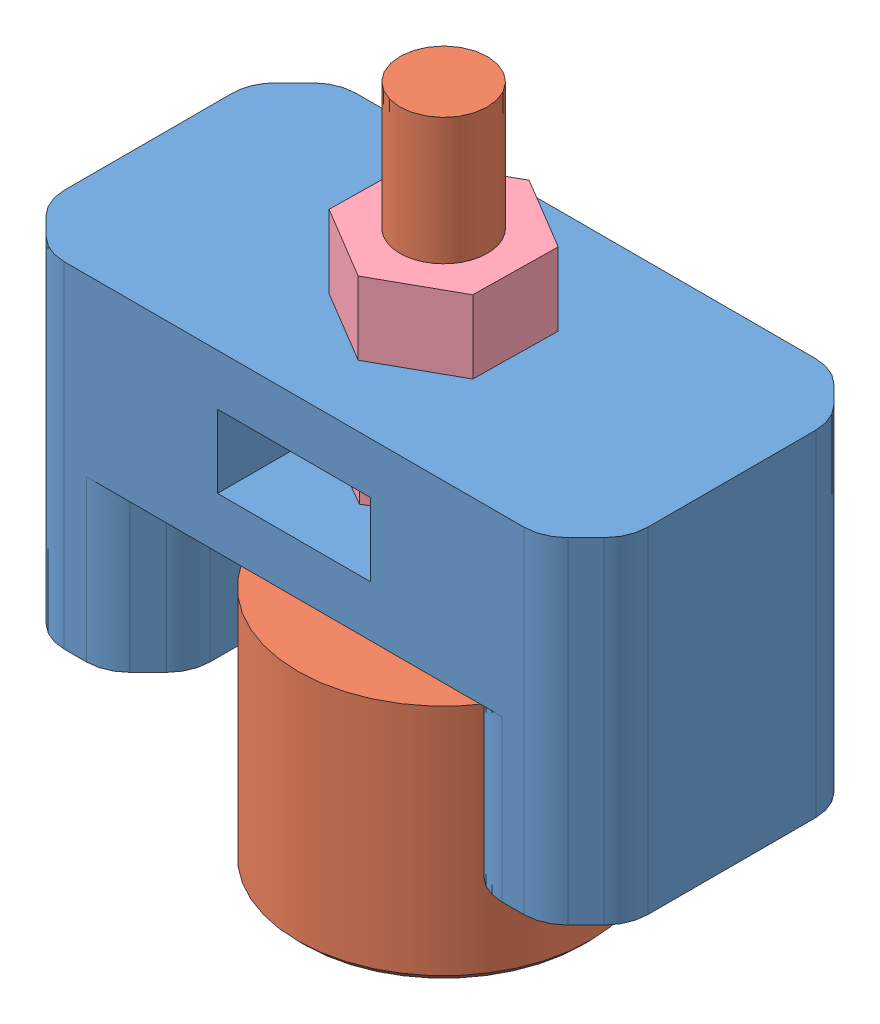
SolidWorks assembly Assemblage Roue Porteuse V2, configuration Défaut. Lengths in mm.
Overall size (40 48.37 24.74).
7 component instances, 5 part files, 13 mates.
Components (placement in the parent):
- Support Bille porteuse V3-1: Support Bille porteuse V3 [Défaut] at (-2.1983 -9.4956 40) size (40 23 20)
- Bille porteuse ALWAYE D12_7-1: Bille porteuse ALWAYE D12_7 [Défaut] at (-1.9483 -8.8075 40) x (-0.275852 0 0.9612) z (-0.9612 0 -0.275852) size (20 46.5 20)
- Bille D12-1: Bille D12 [Défaut] at (-1.9483 -15.1809 40) x (-0.936061 0 0.351838) z (-0.351838 0 -0.936061) size (12 12 12)
- Ecrou M6-3: Ecrou M6 [Défaut] at (-1.9483 13.5044 40) x (0.999888 0 0.014972) z (-0.014972 0 0.999888) size (10 5 11.55)
- Ecrou M6-4: Ecrou M6 [Défaut] at (-1.9483 5.0044 40) size (10 5 11.55)
- Insert_M3x8x5-1: Insert_M3x8x5 [Défaut] at (-17.1983 -9.4956 40) size (4 8 4)
- Insert_M3x8x5-2: Insert_M3x8x5 [Défaut] at (12.8017 -9.4956 40) size (4 8 4)
Mates (geometry in assembly coordinates):
- Coaxiale6: concentric: cylinder of Bille porteuse ALWAYE D12_7-1 through (-1.9483 -18.8075 40) axis (0 1 0) radius 6.75; sphere of Bille D12-1
- Tangent5: tangent: circle of Bille porteuse ALWAYE D12_7-1; sphere of Bille D12-1
- Verrouiller1: lock: unknown of Bille porteuse ALWAYE D12_7-1; unknown of Bille D12-1
- Coïncidente5: coincident anti-aligned: plane of Support Bille porteuse V2-1 through (3.0517 10.0044 30) normal (-1 0 0); plane of Ecrou M6-4 through (3.0517 10.0044 37.1132) normal (1 0 0)
- Coaxiale7: concentric aligned: cylinder of Bille porteuse ALWAYE D12_7-1 through (-1.9483 27.1925 40) axis (0 -1 0) radius 3; cylinder of Ecrou M6-4 through (-1.9483 10.0044 40) axis (0 -1 0) radius 3
- Coïncidente6: coincident anti-aligned: plane of Support Bille porteuse V2-1 through (-2.1983 5.0044 40) normal (0 1 0); plane of Ecrou M6-4 through (-1.9483 5.0044 40) normal (0 -1 0)
- Coaxiale8: concentric aligned: cylinder of Bille porteuse ALWAYE D12_7-1 through (-1.9483 27.1925 40) axis (0 -1 0) radius 3; cylinder of Ecrou M6-3 through (-1.9483 18.5044 40) axis (0 -1 0) radius 3
- Coïncidente7: coincident anti-aligned: plane of Support Bille porteuse V2-1 through (-2.1983 13.5044 40) normal (0 1 0); plane of Ecrou M6-3 through (-1.9483 13.5044 40) normal (0 -1 0)
- Coïncidente8: coincident: point of Support Bille porteuse V2-1; unknown of Ecrou M6-4
- Coaxiale9: concentric: cylinder of Support Bille porteuse V3-1 through (12.8017 5.5044 40) axis (0 -1 0) radius 2; cylinder of Insert_M3x8x5-2 through (12.8017 -1.4956 40) axis (0 -1 0) radius 2
- Coaxiale10: concentric: line of assembly; cylinder of assembly; axis of Support Bille porteuse V3-1 through (-17.1983 5.5044 40) axis (0 -1 0); cylinder of Insert_M3x8x5-1 through (-17.1983 -1.4956 40) axis (0 -1 0) radius 2
- Coïncidente9: coincident aligned: plane of Support Bille porteuse V3-1 through (-2.1983 -9.4956 40) normal (0 -1 0); plane of Insert_M3x8x5-1 through (-17.1983 -9.4956 40) normal (0 -1 0)
- Coïncidente10: coincident aligned: plane of Support Bille porteuse V3-1 through (-2.1983 -9.4956 40) normal (0 -1 0); plane of Insert_M3x8x5-2 through (12.8017 -9.4956 40) normal (0 -1 0)
